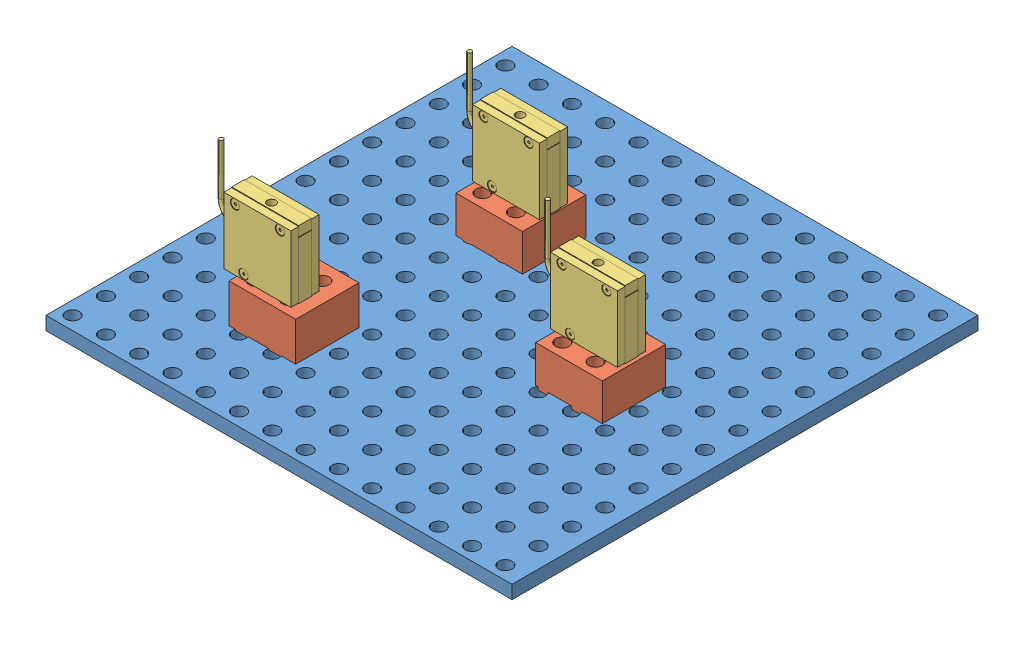
SolidWorks assembly Assem2, configuration Default. Lengths in mm.
Overall size (749.42 115.35 730.7).
7 component instances, 3 part files, 0 mates.
Components (placement in the parent):
- Copy of optic-table^connector+loadcells+optictable-2: Copy of optic-table^connector+loadcells+optictable [Default] at (63.8139 267.2898 556.5175) size (525 10 525) (virtual)
- optic-table-connector-v2-1: optic-table-connector-v2 [Default] at (-160.6024 276.5146 494.5397) size (525 70 525)
- ULC-1: ULC [Default] at (158.0712 334.7587 491.989) size (64.58 73.28 21.21)
- optic-table-connector-v2-4: optic-table-connector-v2 [Default] at (-133.9783 275.0817 350.813) size (525 70 525)
- ULC-4: ULC [Default] at (316.0591 331.1012 404.7168) size (64.58 73.28 21.21)
- ULC-5: ULC [Default] at (191.384 331.7497 338.6193) size (64.58 73.28 21.21)
- optic-table-connector-v2-5: optic-table-connector-v2 [Default] at (-6.7998 275.0817 418.1018) size (525 70 525)
